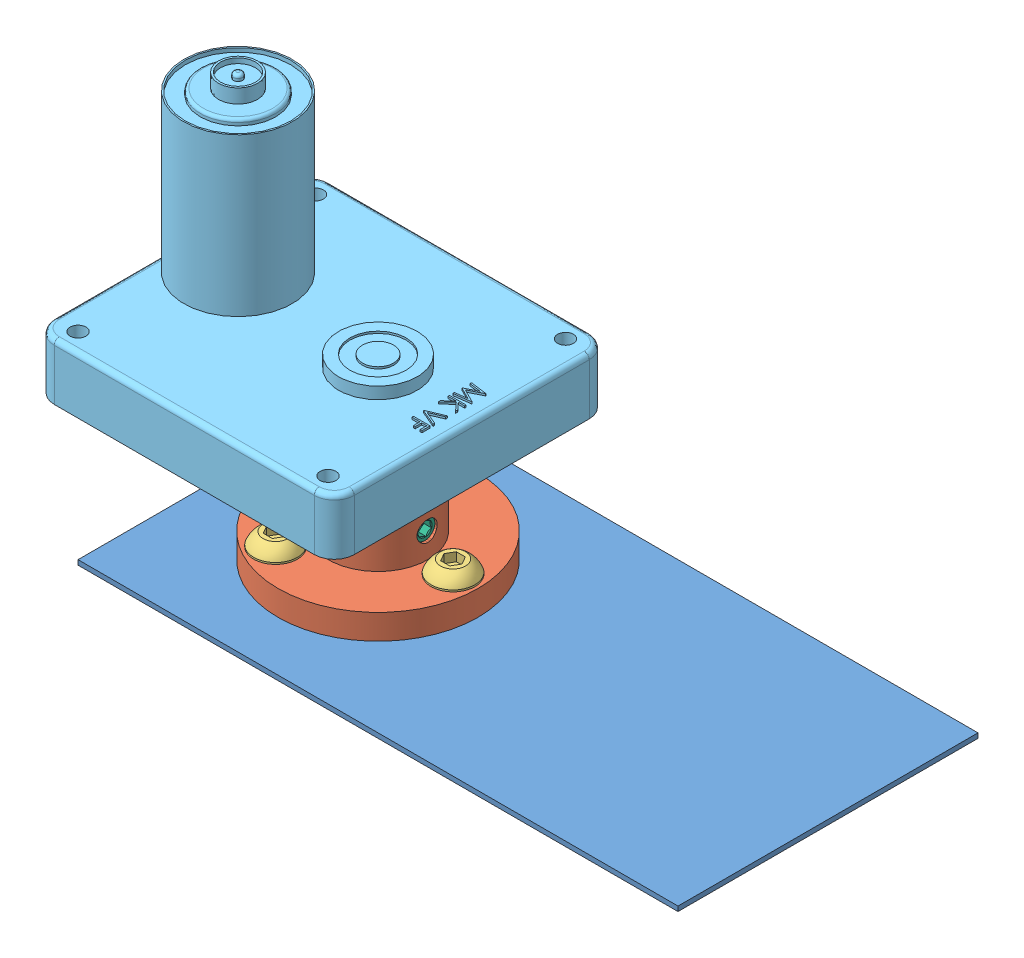
SolidWorks assembly Motorized Dispenser, configuration Default. Lengths in mm.
Overall size (166.69 95.97 76.2).
11 component instances, 6 part files, 5 mates.
Components (placement in the parent):
- Gate-1: Gate [Gate Assembly] at (40.722 74.7431 128.7626) size (152.4 26.67 76.2)
  - Dispenser Gate-1: Dispenser Gate [Default] at (-31.0966 74.0903 164.6921) size (152.4 1.22 76.2)
  - Gate Hub-1: Gate Hub [Gate Hub] at (7.0034 95.6295 126.5921) x (0 0 -1) z (0 -1 0) size (50.8 50.8 20.32)
  - 0.25-20 Button Head Cap Screw (BHCS)-1: 0.25-20 Button Head Cap Screw (BHCS) [Default] at (-2.5216 85.0123 143.0899) x (1 0 0) z (0 -1 0) size (11.1 11.1 16.05)
  - 0.25-20 Button Head Cap Screw (BHCS)-2: 0.25-20 Button Head Cap Screw (BHCS) [Default] at (-2.5216 85.0123 110.0943) x (1 0 0) z (0 -1 0) size (11.1 11.1 16.05)
  - 0.25-20 Button Head Cap Screw (BHCS)-3: 0.25-20 Button Head Cap Screw (BHCS) [Default] at (26.0534 85.0123 126.5921) x (1 0 0) z (0 -1 0) size (11.1 11.1 16.05)
  - 80-20 0.25-20 T-NUT-1: 80-20 0.25-20 T-NUT [Default] at (-120.8742 74.0903 17.1569) x (1 0 0) z (0 -1 0) size (25.4 11.25 2.41)
  - 80-20 0.25-20 T-NUT-2: 80-20 0.25-20 T-NUT [Default] at (-120.8742 74.0903 -15.8387) x (1 0 0) z (0 -1 0) size (25.4 11.25 2.41)
  - 80-20 0.25-20 T-NUT-3: 80-20 0.25-20 T-NUT [Default] at (-99.8797 74.0903 244.9447) x (0 0 -1) z (0 -1 0) size (25.4 11.25 2.41)
- 17.5 RPM Molon Gear Motor-1: 17.5 RPM Molon Gear Motor [Predeterminado] at (33.4378 192.2801 255.3547) x (0 0 -1) z (0 -1 0) size (69.85 76.2 87.08)
- 3-8 Inch 0.25-20 Set Screw-1: 3-8 Inch 0.25-20 Set Screw [91375A535] at (55.3918 162.7526 255.3547) x (0 0.170115 -0.985424) z (1 0 0) size (6.35 6.35 9.71)
Mates (geometry in assembly coordinates):
- Concentric1: concentric aligned: cylinder of Gate-1/Gate Hub-1 through (47.7253 150.0526 255.3547) axis (0 1 0) radius 4.064; cylinder of 17.5 RPM Molon Gear Motor-1 through (47.7253 152.5926 255.3547) axis (0 1 0) radius 3.9688
- Distance1: distance = 2.54 mm anti-aligned: plane of 17.5 RPM Molon Gear Motor-1 through (47.7253 152.5926 255.3547) normal (0 -1 0); plane of Gate-1/Dispenser Gate-1 through (9.6253 150.0526 293.4547) normal (0 1 0)
- Perpendicular1: perpendicular: line of Gate-1/Dispenser Gate-1 through (162.0253 150.0526 217.2547) axis (-1 0 0); plane of 17.5 RPM Molon Gear Motor-1 through (50.1066 152.5926 259.3235) normal (1 0 0)
- Concentric2: concentric aligned: cylinder of Gate-1/Gate Hub-1 through (60.4253 162.7526 255.3547) axis (1 0 0) radius 2.5527; cylinder of 3-8 Inch 0.25-20 Set Screw-1 through (51.152 162.7526 255.3547) axis (1 0 0) radius 3.175
- Coincident1: coincident aligned: plane of 17.5 RPM Molon Gear Motor-1 through (50.1066 152.5926 259.3235) normal (1 0 0); circle of 3-8 Inch 0.25-20 Set Screw-1
